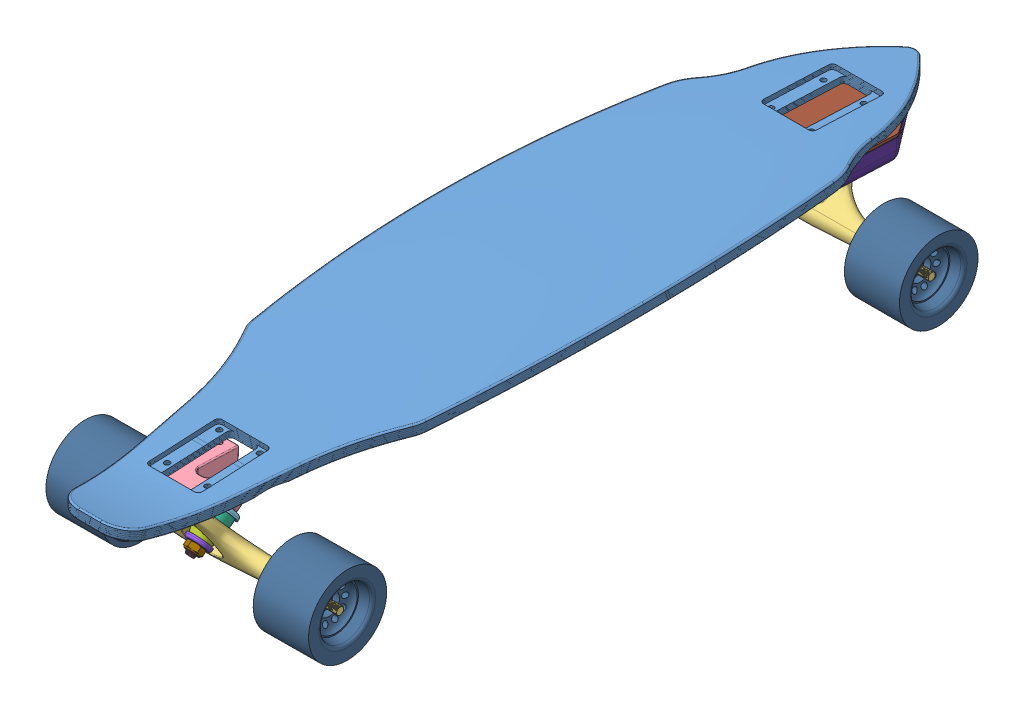
SolidWorks assembly FullAssem, configuration Default. Lengths in mm.
Overall size (266.41 157.6 846.49).
69 component instances, 22 part files, 7 mates.
Components (placement in the parent):
- DeckAndTrucks-1: DeckAndTrucks [Default] at (-8.9962 14.5202 -63.9842) size (266.41 157.6 846.49)
  - Chamber Deck-2: Chamber Deck [Default] at origin size (203.4 42.87 846.49)
  - Truck Cutout-1: Truck Cutout [Default] at (0 15.4335 -251.2196) x (-1 0 0) z (0 0.040365 0.999185) size (652.75 200 200) (hidden)
  - Truck Cutout-2: Truck Cutout [Default] at (0 12.2172 374.2126) x (1 0 0) z (0 0.044825 -0.998995) size (652.75 200 200) (hidden)
  - Truck-2: Truck [Default] at (27.686 -6.6481 -210.3024) x (1 0 0) z (0 -0.0403 -0.999188) size (265.5 107.22 102.66)
    - Rubber Bushing-1: Rubber Bushing [Default] at (-27.686 9.105 71.5015) x (-0.125245 -0.637726 -0.760012) z (0 0.766044 -0.642788) size (17.78 17.78 15.24)
    - Truck Black-1: Truck Black [Default] at (-27.686 18.8338 63.3381) x (1 0 0) z (0 -0.766044 0.642788) size (251.63 24.69 81.31)
    - Truck Silver-1: Truck Silver [Default] at (-27.686 0 0) x (-1 0 0) z (0 0 -1) size (55.37 68.72 102.66)
    - Large Washer-1: Large Washer [Default] at (-27.686 37.0748 22.445) x (1 0 0) z (0 -0.642788 -0.766044) size (29.97 29.97 4.65)
    - Fat Bushing-1: Fat Bushing [Default] at (-27.686 38.3809 24.0016) x (0.983823 -0.137233 0.115152) z (-0.179144 -0.753652 0.632389) size (25.4 13.76 25.4)
    - Small Bushing-1: Small Bushing [Default] at (-27.686 49.674 37.4601) x (0.221595 -0.747 0.626807) z (0 -0.642788 -0.766044) size (25.4 25.4 13.33)
    - Small Washer-1: Small Washer [Default] at (-27.686 59.5517 49.2319) x (0.99468 -0.07891 0.066213) z (0 0.642788 0.766044) size (23.24 23.24 4.15)
    - 3_8 nut-1: 3_8 nut [94945A218] at (-27.686 59.5517 49.2319) x (1 0 0) z (0 -0.766044 0.642788) size (14.29 7.02 16.5)
    - Kegel 80mm longboard wheel-1: Kegel 80mm longboard wheel [Default] at (-123.0988 64.6541 29.035) x (0 -0.998139 0.06098) z (0 0.06098 0.998139) size (80 56 80)
    - Kegel 80mm longboard wheel-2: Kegel 80mm longboard wheel [Default] at (67.7268 64.6541 29.035) x (0 -0.998139 0.06098) z (0 -0.06098 -0.998139) size (80 56 80)
  - Truck-4: Truck [Default] at (-28.5015 -3.4029 334.0274) x (-0.999975 0.000286 0.007074) z (0.00708 0.040364 0.99916) size (265.5 107.22 102.66)
    - Rubber Bushing-1: Rubber Bushing [Default] at (-27.686 9.105 71.5015) x (-0.125245 -0.637726 -0.760012) z (0 0.766044 -0.642788) size (17.78 17.78 15.24)
    - Truck Black-1: Truck Black [Default] at (-27.686 18.8338 63.3381) x (1 0 0) z (0 -0.766044 0.642788) size (251.63 24.69 81.31)
    - Truck Silver-1: Truck Silver [Default] at (-27.686 0 0) x (-1 0 0) z (0 0 -1) size (55.37 68.72 102.66)
    - Large Washer-1: Large Washer [Default] at (-27.686 37.0748 22.445) x (1 0 0) z (0 -0.642788 -0.766044) size (29.97 29.97 4.65)
    - Fat Bushing-1: Fat Bushing [Default] at (-27.686 38.3809 24.0016) x (0.983823 -0.137233 0.115152) z (-0.179144 -0.753652 0.632389) size (25.4 13.76 25.4)
    - Small Bushing-1: Small Bushing [Default] at (-27.686 49.674 37.4601) x (0.221595 -0.747 0.626807) z (0 -0.642788 -0.766044) size (25.4 25.4 13.33)
    - Small Washer-1: Small Washer [Default] at (-27.686 59.5517 49.2319) x (0.99468 -0.07891 0.066213) z (0 0.642788 0.766044) size (23.24 23.24 4.15)
    - 3_8 nut-1: 3_8 nut [94945A218] at (-27.686 59.5517 49.2319) x (1 0 0) z (0 -0.766044 0.642788) size (14.29 7.02 16.5)
    - Kegel 80mm longboard wheel-1: Kegel 80mm longboard wheel [Default] at (-123.0988 64.6541 29.035) x (0 -0.998139 0.06098) z (0 0.06098 0.998139) size (80 56 80)
    - Kegel 80mm longboard wheel-2: Kegel 80mm longboard wheel [Default] at (67.7268 64.6541 29.035) x (0 -0.998139 0.06098) z (0 -0.06098 -0.998139) size (80 56 80)
- SkateLight-1: SkateLight [Default] at (-16.5458 32.2003 -307.5169) x (-1 0 0) z (0 0.0403 0.999188) size (116.7 28.63 114.3)
  - BasePlate-1: BasePlate [Default] at (-7.5496 14.2176 -7.401) size (114.3 2.54 114.3)
  - MainPCB-1: MainPCB [Default] at (0 18.0276 0) x (1 0 0) z (0 1 0) size (104.14 102.87 1.6)
  - Battery_clip_36-54-ND -1: Battery_clip_36-54-ND  [Default] at (-51.2521 28.7716 25.0336) size (16.51 19.53 13.31)
  - Battery_clip_36-54-ND -2: Battery_clip_36-54-ND  [Default] at (-51.2521 28.7716 -16.9757) x (-1 0 0) z (0 0 -1) size (16.51 19.53 13.31)
  - Battery_clip_36-54-ND -3: Battery_clip_36-54-ND  [Default] at (36.1529 28.7716 25.0336) size (16.51 19.53 13.31)
  - Battery_clip_36-54-ND -4: Battery_clip_36-54-ND  [Default] at (36.1529 28.7716 -16.9757) x (-1 0 0) z (0 0 -1) size (16.51 19.53 13.31)
  - Battery Samsung ICR 18650 -22E-1: Battery Samsung ICR 18650 -22E [Default] at (-53.9398 16.5997 -26.2895) x (0 0 1) z (0.612724 -0.790297 0) size (65 18 18)
    - Battery Samsung ICR 18650 -22E.stp-1: Battery Samsung ICR 18650 -22E.stp [Default] at origin size (65 18 18)
      - Samsung_ICR18650-22E.stp-1: Samsung_ICR18650-22E.stp [Default] at (-2.1716 -9.5821 -7.9726) x (0 0 -1) z (1 0 0) size (18 18 65)
  - Battery Samsung ICR 18650 -22E-2: Battery Samsung ICR 18650 -22E [Default] at (23.6951 28.3421 -26.2895) x (0 0 1) z (-0.612724 -0.790297 0) size (65 18 18)
    - Battery Samsung ICR 18650 -22E.stp-1: Battery Samsung ICR 18650 -22E.stp [Default] at origin size (65 18 18)
      - Samsung_ICR18650-22E.stp-1: Samsung_ICR18650-22E.stp [Default] at (-2.1716 -9.5821 -7.9726) x (0 0 -1) z (1 0 0) size (18 18 65)
  - PCB_FRO-1: PCB_FRO [Default] at (-19.6838 18.3609 -58.3144) x (-1 0 0) z (0 0 -1) size (46.48 5.08 2.12)
    - LEDPanel-1: LEDPanel [Default] at (-12.1342 0.9368 4.9666) size (46.48 5.08 1.6)
    - 1206_5000k_LUMINUS_MP3014_1100-1: 1206_5000k_LUMINUS_MP3014_1100 [Default] at (-32.1186 1.0071 6.5666) x (1 0 0) z (0 -1 0) size (1.4 0.52 3)
    - 1206_5000k_LUMINUS_MP3014_1100-2: 1206_5000k_LUMINUS_MP3014_1100 [Default] at (-26.4036 1.0071 6.5666) x (1 0 0) z (0 -1 0) size (1.4 0.52 3)
    - 1206_5000k_LUMINUS_MP3014_1100-3: 1206_5000k_LUMINUS_MP3014_1100 [Default] at (-20.6886 1.0071 6.5666) x (1 0 0) z (0 -1 0) size (1.4 0.52 3)
    - 1206_5000k_LUMINUS_MP3014_1100-4: 1206_5000k_LUMINUS_MP3014_1100 [Default] at (-14.9736 1.0071 6.5666) x (1 0 0) z (0 -1 0) size (1.4 0.52 3)
    - 1206_5000k_LUMINUS_MP3014_1100-5: 1206_5000k_LUMINUS_MP3014_1100 [Default] at (-9.2586 1.0071 6.5666) x (1 0 0) z (0 -1 0) size (1.4 0.52 3)
    - 1206_5000k_LUMINUS_MP3014_1100-6: 1206_5000k_LUMINUS_MP3014_1100 [Default] at (-3.5436 1.0071 6.5666) x (1 0 0) z (0 -1 0) size (1.4 0.52 3)
    - 1206_5000k_LUMINUS_MP3014_1100-7: 1206_5000k_LUMINUS_MP3014_1100 [Default] at (2.1714 1.0071 6.5666) x (1 0 0) z (0 -1 0) size (1.4 0.52 3)
    - 1206_5000k_LUMINUS_MP3014_1100-8: 1206_5000k_LUMINUS_MP3014_1100 [Default] at (7.8864 1.0071 6.5666) x (1 0 0) z (0 -1 0) size (1.4 0.52 3)
  - TopPlate-1: TopPlate [Default] at (-7.5496 24.8856 -7.401) x (-1 0 0) z (0 0 1) size (116.7 25.59 114.3)
  - PCB_SIDE_LEd-1: PCB_SIDE_LEd [Default] at (-44.6701 18.3609 -35.1604) x (-0.573576 0 0.819152) z (-0.819152 0 -0.573576) size (37.46 5.08 2.12)
    - LEDPanel2-1: LEDPanel2 [Default] at (-12.1342 0.9368 4.9666) size (37.46 5.08 1.6)
    - 1206_5000k_LUMINUS_MP3014_1100-1: 1206_5000k_LUMINUS_MP3014_1100 [Default] at (-26.7929 0.8779 6.5666) x (1 0 0) z (0 -1 0) size (1.4 0.52 3)
    - 1206_5000k_LUMINUS_MP3014_1100-2: 1206_5000k_LUMINUS_MP3014_1100 [Default] at (-21.0779 0.8779 6.5666) x (1 0 0) z (0 -1 0) size (1.4 0.52 3)
    - 1206_5000k_LUMINUS_MP3014_1100-3: 1206_5000k_LUMINUS_MP3014_1100 [Default] at (-15.3629 0.8779 6.5666) x (1 0 0) z (0 -1 0) size (1.4 0.52 3)
    - 1206_5000k_LUMINUS_MP3014_1100-4: 1206_5000k_LUMINUS_MP3014_1100 [Default] at (-9.6479 0.8779 6.5666) x (1 0 0) z (0 -1 0) size (1.4 0.52 3)
    - 1206_5000k_LUMINUS_MP3014_1100-5: 1206_5000k_LUMINUS_MP3014_1100 [Default] at (-3.9329 0.8779 6.5666) x (1 0 0) z (0 -1 0) size (1.4 0.52 3)
    - 1206_5000k_LUMINUS_MP3014_1100-9: 1206_5000k_LUMINUS_MP3014_1100 [Default] at (1.7821 0.8779 6.5666) x (1 0 0) z (0 -1 0) size (1.4 0.52 3)
  - PCB_SIDE_LEd-2: PCB_SIDE_LEd [Default] at (29.5708 20.2344 -35.1604) x (0.573576 0 0.819152) z (0.819152 0 -0.573576) size (37.46 5.08 2.12)
    - LEDPanel2-1: LEDPanel2 [Default] at (-12.1342 0.9368 4.9666) size (37.46 5.08 1.6)
    - 1206_5000k_LUMINUS_MP3014_1100-1: 1206_5000k_LUMINUS_MP3014_1100 [Default] at (-26.7929 0.8779 6.5666) x (1 0 0) z (0 -1 0) size (1.4 0.52 3)
    - 1206_5000k_LUMINUS_MP3014_1100-2: 1206_5000k_LUMINUS_MP3014_1100 [Default] at (-21.0779 0.8779 6.5666) x (1 0 0) z (0 -1 0) size (1.4 0.52 3)
    - 1206_5000k_LUMINUS_MP3014_1100-3: 1206_5000k_LUMINUS_MP3014_1100 [Default] at (-15.3629 0.8779 6.5666) x (1 0 0) z (0 -1 0) size (1.4 0.52 3)
    - 1206_5000k_LUMINUS_MP3014_1100-4: 1206_5000k_LUMINUS_MP3014_1100 [Default] at (-9.6479 0.8779 6.5666) x (1 0 0) z (0 -1 0) size (1.4 0.52 3)
    - 1206_5000k_LUMINUS_MP3014_1100-5: 1206_5000k_LUMINUS_MP3014_1100 [Default] at (-3.9329 0.8779 6.5666) x (1 0 0) z (0 -1 0) size (1.4 0.52 3)
    - 1206_5000k_LUMINUS_MP3014_1100-9: 1206_5000k_LUMINUS_MP3014_1100 [Default] at (1.7821 0.8779 6.5666) x (1 0 0) z (0 -1 0) size (1.4 0.52 3)
  - LEDScreen-2: LEDScreen [Default] at (-7.5496 18.0276 -66.456) x (-1 0 0) z (0 0 -1) size (104.09 8.13 38.1)
  - ESP-WROOM-32-1: ESP-WROOM-32 [Default] at (-7.6579 19.6276 -4.0378) x (1 0 0) z (0 1 0) size (18.07 25.54 3.04)
  - Hirose Micro USB Digikey PN H11635CT-ND-1: Hirose Micro USB Digikey PN H11635CT-ND [Default] at (-7.526 20.8976 40.1422) size (8.8 3 5.6)
Mates (geometry in assembly coordinates):
- Parallel4: parallel: plane of DeckAndTrucks-1/Truck-2/Truck Silver-1 through (-8.9962 2.1618 -274.0562) normal (0 0.0403 0.999188); plane of ? through (-9.0207 8.3623 -372.43) normal (0 0.0403 0.999188)
- Parallel5: parallel: plane of DeckAndTrucks-1/Truck-2/Truck Silver-1 through (-8.9962 7.8721 -274.2865) normal (0 0.999188 -0.0403); plane of ? through (16.3793 11.4703 -374.1567) normal (0 0.999188 -0.0403)
- Distance2: distance = 6.35 mm: plane of SkateLight-1/BasePlate-1 through (-8.9962 12.6201 -314.1343) normal (0 -0.999188 0.0403); plane of DeckAndTrucks-1/Truck-2/Truck Silver-1 through (-8.9962 7.8721 -274.2865) normal (0 0.999188 -0.0403)
- Parallel6: parallel: plane of DeckAndTrucks-1/Truck-2/Truck Silver-1 through (18.6898 2.1618 -274.0562) normal (1 0 0); plane of SkateLight-1/BasePlate-1 through (2.1163 12.6201 -314.1343) normal (-1 0 0)
- Concentric1: concentric: cylinder of DeckAndTrucks-1/Truck-2/Truck Silver-1 through (11.6413 -0.7146 -345.3723) axis (0 0.999188 -0.0403) radius 2.794; cylinder of SkateLight-1/BasePlate-1 through (11.6413 11.3406 -345.8585) axis (0 0.999188 -0.0403) radius 2.3813
- Coincident9: coincident: plane of ? through (16.3793 11.4703 -374.1567) normal (0 0.999188 -0.0403); plane of SkateLight-1/MainPCB-1 through (-16.5458 14.1873 -306.7904) normal (0 0.999188 -0.0403)
- Coincident10: coincident: plane of ? through (-9.0207 8.3623 -372.43) normal (0 0.0403 0.999188); plane of SkateLight-1/MainPCB-1 through (-16.5458 9.9361 -372.4935) normal (0 -0.0403 -0.999188)
